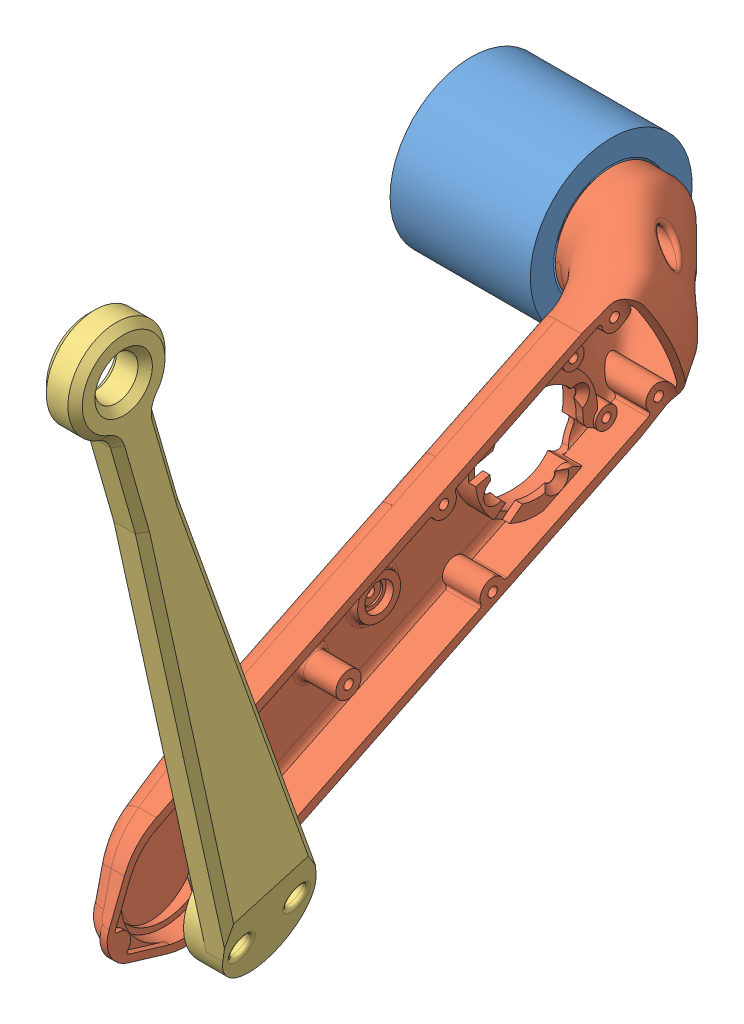
SolidWorks assembly roboleg1, configuration Default. Lengths in mm.
Overall size (91.5 197.07 227.31).
3 component instances, 3 part files, 4 mates.
Components (placement in the parent):
- Part11-1: Part11 [Default] at (67.6209 148.5124 268.3595) x (0 0 -1) z (1 0 0) size (45 45 39)
- upper leg module shell base-1: upper leg module shell base [Default] at (125.6209 105.2775 357.4198) x (0 -0.899599 -0.436716) z (0 -0.436716 0.899599) size (37.02 37.51 198.25)
- lower leg-1: lower leg [Default] at (159.1209 155.5293 434.3793) x (0 0.961144 0.276049) z (0 -0.276049 0.961144) size (187 20 27)
Mates (geometry in assembly coordinates):
- Concentric1: concentric anti-aligned: cylinder of Part11-1 through (106.6209 148.5124 268.3595) axis (-1 0 0) radius 16; cylinder of upper leg module shell base-1 through (105.1209 148.5124 268.3595) axis (1 0 0) radius 13.75
- Coincident1: coincident anti-aligned: plane of Part11-1 through (106.6209 148.5124 268.3595) normal (1 0 0); plane of upper leg module shell base-1 through (106.6209 148.5124 268.3595) normal (-1 0 0)
- Concentric2: concentric aligned: cylinder of upper leg module shell base-1 through (126.1209 78.6378 412.2954) axis (1 0 0) radius 16; cylinder of lower leg-1 through (149.1209 78.6378 412.2954) axis (1 0 0) radius 13.5
- Distance1: distance = 15 mm anti-aligned: plane of upper leg module shell base-1 through (130.1209 70.2556 393.4974) normal (1 0 0); plane of lower leg-1 through (145.1209 78.6378 412.2954) normal (-1 0 0)
